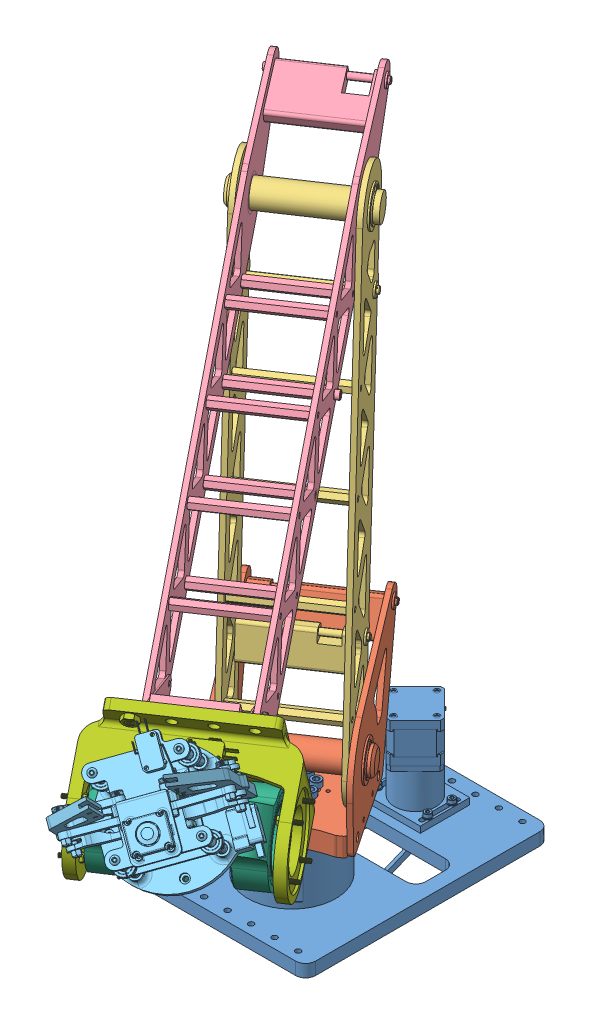
SolidWorks assembly sm_robot, configuration Default. Lengths in mm.
Overall size (599.65 817.35 772.67).
7 component instances, 7 part files, 13 mates.
Components (placement in the parent):
- UOR23-ARM-2-A-002_Base-1: UOR23-ARM-2-A-002_Base [Default] at (116.2596 86.0783 329.6514) size (177.81 113.36 246.81)
- UOR23-ARM-2-A-006_Hip-1: UOR23-ARM-2-A-006_Hip [Default] at (112.4993 86.0783 160.4538) x (-0.678787 0 -0.734335) z (0.734335 0 -0.678787) size (178.67 138.46 139.2)
- UOR23-ARM-2-A-005_Arm-1: UOR23-ARM-2-A-005_Arm [Default] at (138.6089 73.5786 199.38) x (-0.644366 -0.343892 -0.68303) z (0.73972 -0.053796 -0.670761) size (188.27 507.54 128.22)
- UOR23-ARM-2-A-004_Forearm-1: UOR23-ARM-2-A-004_Forearm [Default] at (-204.9448 545.4872 -312.6914) x (-0.380052 0.878636 -0.289067) z (0.781067 0.137448 -0.609133) size (501.22 355.31 160.08)
- UOR23-ARM-1-A-001_EE-1: UOR23-ARM-1-A-001_EE [Default] at (432.6795 425.175 661.437) x (-0.637204 -0.285731 0.715772) z (-0.641549 0.711295 -0.287184) size (143.27 218.85 114.13)
- UOR23-ARM-2-A-007_Wrist_A-1: UOR23-ARM-2-A-007_Wrist_A [Default] at (229.5753 314.6179 586.2435) x (0.427068 0.642197 0.63655) z (-0.83042 0 0.557137) size (112 84.31 134)
- UOR23-ARM-2-A-007_Wrist_B-1: UOR23-ARM-2-A-007_Wrist_B [Default] at (228.9509 421.7571 524.201) x (0.482496 -0.499997 0.719167) z (-0.83042 0 0.557137) size (114 122 176.57)
Mates (geometry in assembly coordinates):
- Concentric1: concentric anti-aligned: circle of UOR23-ARM-2-A-002_Base-1; circle of UOR23-ARM-2-A-006_Hip-1
- Coincident1: coincident anti-aligned: plane of UOR23-ARM-2-A-002_Base-1 through (77.3742 160.2783 245.875) normal (0 1 0); plane of UOR23-ARM-2-A-006_Hip-1 through (77.3742 160.2783 245.875) normal (0 -1 0)
- Concentric2: concentric aligned: circle of UOR23-ARM-2-A-006_Hip-1; circle of UOR23-ARM-2-A-005_Arm-1
- Coincident2: coincident anti-aligned: plane of UOR23-ARM-2-A-006_Hip-1 through (123.3787 210.2783 223.2687) normal (-0.83042 0 0.557137); plane of UOR23-ARM-2-A-005_Arm-1 through (123.3787 210.2783 223.2687) normal (0.83042 0 -0.557137)
- Concentric3: concentric aligned: circle of UOR23-ARM-2-A-005_Arm-1; circle of UOR23-ARM-2-A-004_Forearm-1
- Coincident3: coincident anti-aligned: plane of UOR23-ARM-2-A-005_Arm-1 through (44.2785 210.2783 276.3378) normal (0.83042 0 -0.557137); plane of UOR23-ARM-2-A-004_Forearm-1 through (14.3528 657.0611 231.733) normal (-0.83042 0 0.557137)
- Coincident4: coincident anti-aligned: plane of UOR23-ARM-2-A-004_Forearm-1 through (261.7864 442.4845 520.7504) normal (0.482496 -0.499997 0.719167); plane of UOR23-ARM-2-A-007_Wrist_B-1 through (129.8201 345.0451 541.5435) normal (-0.482496 0.499997 -0.719167)
- Concentric4: concentric aligned: circle of UOR23-ARM-2-A-004_Forearm-1; circle of UOR23-ARM-2-A-007_Wrist_B-1
- Coincident6: coincident aligned: plane of UOR23-ARM-2-A-004_Forearm-1 through (251.6076 495.3122 564.3076) normal (0.278567 0.866027 0.415208); plane of UOR23-ARM-2-A-007_Wrist_B-1 through (333.0636 495.3122 509.658) normal (0.278567 0.866027 0.415208)
- Concentric5: concentric anti-aligned: circle of UOR23-ARM-2-A-007_Wrist_A-1; circle of UOR23-ARM-2-A-007_Wrist_B-1
- Distance1: distance = 5 mm anti-aligned: plane of UOR23-ARM-2-A-007_Wrist_A-1 through (238.9558 408.4847 606.9834) normal (-0.83042 0 0.557137); plane of UOR23-ARM-2-A-007_Wrist_B-1 through (245.5773 349.9778 625.8272) normal (0.83042 0 -0.557137)
- Concentric6: concentric aligned: circle of UOR23-ARM-1-A-001_EE-1; circle of UOR23-ARM-2-A-007_Wrist_A-1
- Coincident9: coincident anti-aligned: plane of UOR23-ARM-1-A-001_EE-1 through (325.6335 455.3651 616.2148) normal (-0.427068 -0.642197 -0.63655); plane of UOR23-ARM-2-A-007_Wrist_A-1 through (325.6335 455.3651 616.2148) normal (0.427068 0.642197 0.63655)
